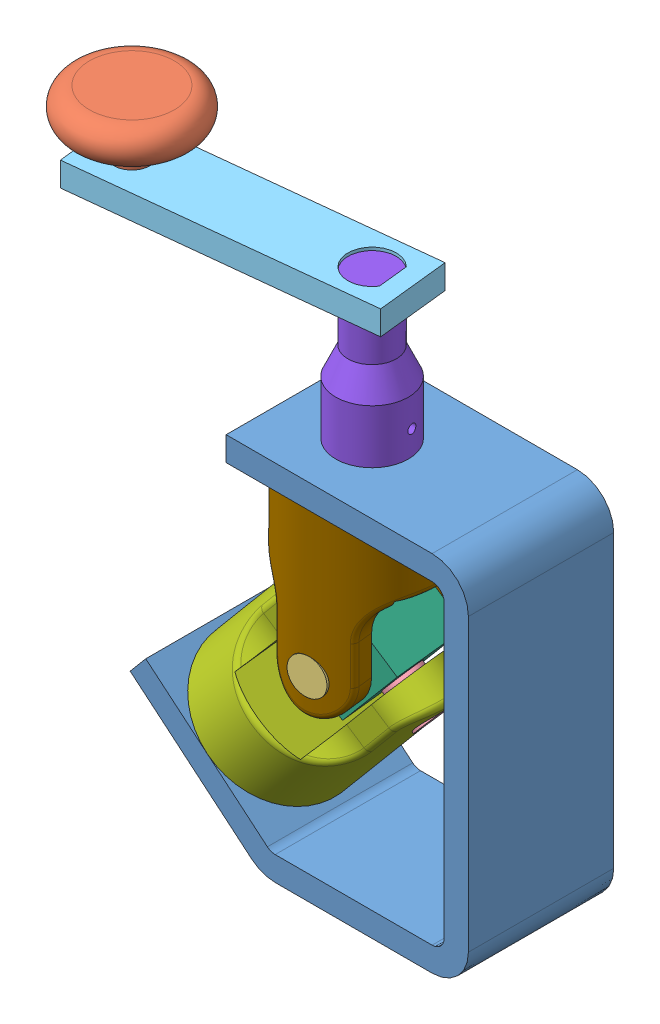
SolidWorks assembly Universal_Joint_assembly, configuration Default. Lengths in mm.
Overall size (117.66 150.01 45.08).
10 component instances, 9 part files, 20 mates.
Components (placement in the parent):
- 1_Part-1: 1_Part [Default] at (93.0215 46.3512 49.4101) size (88.66 95.25 38.1)
- 2_Part-1: 2_Part [Default] at (-7.3917 137.6262 75.3058) x (0.995954 0 -0.089865) z (0.089865 0 0.995954) size (31.76 22.22 31.76)
- 3_Part-1: 3_Part [Default] at (50.6001 49.5862 87.3996) x (-0.994201 0 0.107538) z (-0.107538 0 -0.994201) size (9.52 9.52 38.1)
- 4_Part-1: 4_Part [Default] at (63.4178 36.1799 66.897) x (0.632527 0.767369 -0.105135) z (-0.763428 0.640592 0.082576) size (9.52 9.52 12.7)
- 5_Part-1: 5_Part [Default] at (22.2158 126.5162 81.6839) x (0.994201 0 -0.107538) z (0.107538 0 0.994201) size (76.2 6.35 19.05)
- 6_Part-1: 6_Part [Default] at (47.4589 49.5862 58.359) x (0.763428 -0.640592 -0.082576) z (0.107538 0 0.994201) size (20.32 20.32 20.32)
- 7_Part-1: 7_Part [Default] at (54.9996 55.6841 68.4601) x (-0.063257 0.053079 -0.996585) z (-0.763428 0.640592 0.082576) size (38.96 47.63 38.1)
- 8_Part-1: 8_Part [Default] at (49.4269 93.9762 69.16) x (0.994201 0 -0.107538) z (0.107538 0 0.994201) size (19.05 38.1 19.05)
- 9_Part-1: 9_Part [Default] at (48.5515 69.2062 68.4601) x (0.994201 0 -0.107538) z (0.107538 0 0.994201) size (38.1 65.38 38.1)
- 4_Part-2: 4_Part [Default] at (44.0267 52.451 68.9944) x (0.632527 0.767369 -0.105135) z (-0.763428 0.640592 0.082576) size (9.52 9.52 12.7)
Mates (geometry in assembly coordinates):
- Concentric1: concentric: cylinder of 2_Part-1 through (-7.3917 174.2865 75.3058) axis (0 1 0) radius 2.38; cylinder of 5_Part-1 through (-7.3917 132.8662 75.3058) axis (0 -1 0) radius 2.38
- Coincident1: coincident: plane of 2_Part-1 through (-5.0214 132.8662 75.0919) normal (0 -1 0); plane of 5_Part-1 through (22.2158 132.8662 81.6839) normal (0 1 0)
- Concentric2: concentric: cylinder of 1_Part-1 through (48.5515 93.9762 68.4601) axis (0 1 0) radius 6.35; cylinder of 9_Part-1 through (48.5515 105.4362 68.4601) axis (0 -1 0) radius 6.35
- Coincident2: coincident: plane of 1_Part-1 through (29.5115 87.6262 87.5101) normal (0 -1 0); plane of 9_Part-1 through (48.5515 87.6262 68.4601) normal (0 1 0)
- Concentric3: concentric: cylinder of 8_Part-1 through (48.5515 108.0362 68.4601) axis (0 -1 0) radius 5.555; cylinder of 9_Part-1 through (48.5515 105.4362 68.4601) axis (0 -1 0) radius 6.35
- Parallel1: parallel: plane of 8_Part-1 through (53.2484 132.0762 60.2273) normal (0.994201 0 -0.107538); plane of 9_Part-1 through (52.3263 105.4362 59.0949) normal (0.994201 0 -0.107538)
- Coincident4: coincident: plane of 1_Part-1 through (29.5115 93.9762 87.5101) normal (0 1 0); plane of 8_Part-1 through (49.4269 93.9762 69.16) normal (0 -1 0)
- Concentric4: concentric: cylinder of 5_Part-1 through (49.4269 132.8662 69.16) axis (0 -1 0) radius 6.35; cylinder of 8_Part-1 through (49.4269 115.1362 69.16) axis (0 1 0) radius 6.35
- Parallel2: parallel: plane of 5_Part-1 through (53.9091 132.8662 64.6621) normal (-0.994201 0 0.107538); plane of 8_Part-1 through (53.2484 132.0762 60.2273) normal (0.994201 0 -0.107538)
- Coincident6: coincident: plane of 5_Part-1 through (22.2158 126.5162 81.6839) normal (0 -1 0); plane of 8_Part-1 through (54.8292 126.5162 60.0563) normal (0 1 0)
- Concentric5: concentric: cylinder of 6_Part-1 through (49.6441 49.5862 78.5612) axis (-0.107538 0 -0.994201) radius 4.675; cylinder of 9_Part-1 through (50.6002 49.5862 87.4006) axis (-0.107538 0 -0.994201) radius 4.765
- Width1: width: plane of 9_Part-1 through (47.2836 49.5862 56.7385) normal (0.107538 0 0.994201); plane of 9_Part-1 through (49.8194 49.5862 80.1817) normal (-0.107538 0 -0.994201); plane of 6_Part-1 through (47.4589 49.5862 58.359) normal (-0.107538 0 -0.994201); plane of 6_Part-1 through (49.6441 49.5862 78.5612) normal (0.107538 0 0.994201)
- Concentric6: concentric: cylinder of 3_Part-1 through (46.5029 49.5862 49.5206) axis (0.107538 0 0.994201) radius 4.76; cylinder of 9_Part-1 through (50.6002 49.5862 87.4006) axis (-0.107538 0 -0.994201) radius 4.765
- Tangent1: tangent: plane of 3_Part-1 through (50.6001 49.5862 87.3996) normal (0.107538 0 0.994201); cylinder of 9_Part-1 through (48.5515 87.6262 68.4601) axis (0 -1 0) radius 19.05
- Coincident7: coincident: circle of 1_Part-1; circle of 7_Part-1
- Parallel3: parallel: cylinder of 6_Part-1 through (56.3079 43.0777 67.6211) axis (0.763428 -0.640592 -0.082576) radius 4.675; cylinder of 7_Part-1 through (69.3458 31.2057 66.2558) axis (-0.763428 0.640592 0.082576) radius 4.765
- Concentric8: concentric: cylinder of 4_Part-1 through (53.7223 44.3154 67.9457) axis (0.763428 -0.640592 -0.082576) radius 4.76; cylinder of 7_Part-1 through (69.3458 31.2057 66.2558) axis (-0.763428 0.640592 0.082576) radius 4.765
- Tangent3: tangent: plane of 4_Part-1 through (63.4178 36.1799 66.897) normal (0.763428 -0.640592 -0.082576); cylinder of 7_Part-1 through (24.3837 19.1974 68.4601) axis (0.642788 0.766044 0) radius 19.05
- Concentric9: concentric: cylinder of 7_Part-1 through (69.3458 31.2057 66.2558) axis (-0.763428 0.640592 0.082576) radius 4.765; cylinder of 4_Part-2 through (34.3312 60.5865 70.0432) axis (0.763428 -0.640592 -0.082576) radius 4.76
- Tangent4: tangent: cylinder of 7_Part-1 through (24.3837 19.1974 68.4601) axis (0.642788 0.766044 0) radius 19.05; plane of 4_Part-2 through (34.3312 60.5865 70.0432) normal (-0.763428 0.640592 0.082576)
